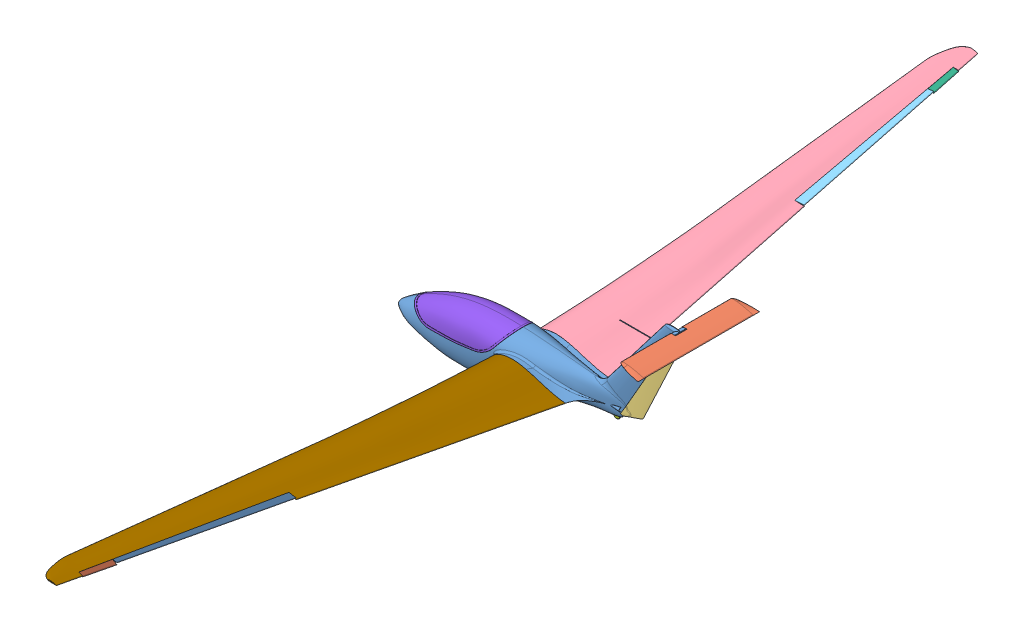
SolidWorks assembly G2, configuration Default. Lengths in mm.
Overall size (4857.56 2154.28 14974.87).
11 component instances, 11 part files, 23 mates.
Components (placement in the parent):
- fuselage-1: fuselage [Default] at (-2399.0476 -678.4623 -6.1761) size (4647.03 2154.28 817.52)
- Elevator-1: Elevator [Default] at (-2592.4679 -10.7116 -6.1761) x (0.990017 -0.140945 0) z (0 0 1) size (369.59 46.81 1973.39)
- TailFin-1: TailFin [Default] at (-2374.746 -692.1121 -425.4765) x (0.993311 0.003757 0.115405) z (-0.115405 0.064821 0.991201) size (1019.44 1537.55 79.37)
- RightWing-1: RightWing [Default] at (64.2546 7069.2767 -6.1761) x (0 0 -1) z (0.997564 -0.069756 0) size (7284.24 424.09 1503.14)
- RightFlap-1: RightFlap [Default] at (-780.4832 6967.3808 106.5214) x (0.005717 0.016013 -0.999855) z (0.999111 0.041673 0.00638) size (2595.89 151.47 516.44)
- RightAileron-1: RightAileron [Default] at (1721.4228 6989.7484 -243.8048) x (-0.016138 -0.029004 -0.999449) z (0.958774 -0.284078 -0.007237) size (509.26 36.38 165.41)
- TailWheel-1: TailWheel [Default] at (1188.0854 -633.4405 -16.4079) size (114.3 114.3 20.26)
- GlassShield-2: GlassShield [Default] at (-2399.0474 -678.4622 -6.1761) size (1997.95 819.79 898.09)
- LeftWing-1: LeftWing [Default] at (64.2546 7069.2767 -6.1761) x (0 0 -1) z (0.997564 -0.069756 0) size (7284.24 424.09 1503.14)
- LeftFlap-1: LeftFlap [Default] at (-1231.8601 6872.378 -176.6913) x (-0.008056 -0.024918 -0.999657) z (0.994746 0.101829 -0.010555) size (2595.89 151.47 516.44)
- LeftAileron-2: LeftAileron [Default] at (1280.1678 7047.2031 166.0311) x (0.011201 0.021593 -0.999704) z (0.973746 -0.22756 0.005995) size (509.26 36.38 165.41)
Mates (geometry in assembly coordinates):
- Concentric2: concentric aligned: cylinder of fuselage-1 through (1289.1653 -580.6894 -6.1761) axis (0.489718 0.871881 0) radius 6.35; cylinder of TailFin-1 through (1289.1653 -580.6894 -6.1761) axis (0.489718 0.871881 0) radius 6.35
- Coincident5: coincident anti-aligned: plane of fuselage-1 through (706.154 -539.7211 -361.7761) normal (0 0 -1); plane of RightWing-1 through (-435.1334 -423.7986 -361.7761) normal (0 0 1)
- Coincident6: coincident anti-aligned: plane of fuselage-1 through (27.8129 -445.2218 -209.3761) normal (-0.990524 0.137342 0); plane of RightWing-1 through (27.8129 -445.2218 -209.3761) normal (0.990524 -0.137342 0)
- Coincident7: coincident anti-aligned: plane of fuselage-1 through (-42.4323 -397.0174 -209.3761) normal (-0.137342 -0.990524 0); plane of RightWing-1 through (-42.4323 -397.0174 -209.3761) normal (0.137342 0.990524 0)
- Concentric3: concentric aligned: cylinder of RightWing-1 through (-27.4915 -301.4668 -4089.8299) axis (-0.138946 0.05853 -0.988569) radius 6.35; cylinder of RightFlap-1 through (-27.4915 -301.4668 -4089.8299) axis (-0.138946 0.05853 -0.988569) radius 6.35
- Coincident8: coincident anti-aligned: plane of RightWing-1 through (-73.6657 -909.8309 -4145.0529) normal (-0.138946 0.05853 -0.988569); plane of RightFlap-1 through (-5.3134 -910.2283 -4154.6836) normal (0.138946 -0.05853 0.988569)
- Concentric4: concentric aligned: cylinder of RightWing-1 through (-455.5258 -122.7684 -7134.4869) axis (0.138946 -0.05853 0.988569) radius 2.54; cylinder of RightAileron-1 through (-455.5258 -122.7684 -7134.4869) axis (0.138946 -0.05853 0.988569) radius 2.54
- Coincident9: coincident anti-aligned: plane of RightWing-1 through (-494.5323 -732.5444 -7139.4135) normal (0.138946 -0.05853 0.988569); plane of RightAileron-1 through (-625.4814 -709.5114 -7119.6445) normal (-0.138946 0.05853 -0.988569)
- Coincident10: coincident anti-aligned: plane of fuselage-1 through (1312.7204 -579.3537 -329.0605) normal (0.489718 0.871881 0); plane of TailFin-1 through (1349.8303 -600.1976 -323.5877) normal (-0.489718 -0.871881 0)
- Concentric5: concentric anti-aligned: cylinder of fuselage-1 through (2218.2489 1020.8694 -133.1761) axis (0 0 -1) radius 6.35; cylinder of Elevator-1 through (2218.2489 1020.8694 -196.2951) axis (0 0 1) radius 6.35
- Coincident11: coincident anti-aligned: plane of fuselage-1 through (2154.7125 1016.738 87.8039) normal (0 0 1); plane of Elevator-1 through (2154.7644 1025.7344 87.8039) normal (0 0 -1)
- Concentric6: concentric anti-aligned: cylinder of fuselage-1 through (1188.0854 -633.4405 499993.8239) axis (0 0 -1) radius 5.08; cylinder of TailWheel-1 through (1188.0854 -633.4405 3.851) axis (0 0 1) radius 2.54
- Coincident12: coincident anti-aligned: plane of fuselage-1 through (1246.6746 -603.6005 -15.1685) normal (0 0 1); plane of TailWheel-1 through (1190.6254 -633.4405 -15.1685) normal (0 0 -1)
- Concentric8: concentric anti-aligned: cylinder of fuselage-1 through (-2030.4334 -612.6736 -12.5261) axis (0 0 1) radius 3.175; cylinder of GlassShield-2 through (-2030.4334 -612.6736 6.5239) axis (0 0 -1) radius 3.175
- LimitAngle2: limit planar angle = 0.462434 rad aligned: plane of GlassShield-2 through (-2024.28 -603.4196 -3.0011) normal (0.525638 0.850708 0); plane of fuselage-1 through (-311924.6085 499347.8255 0.1739) normal (0.849955 0.526856 0)
- Coincident25: coincident anti-aligned: plane of fuselage-1 through (-2030.4334 -612.6736 -9.3511) normal (0 0 1); plane of GlassShield-2 through (-2030.4308 -612.6746 -9.3511) normal (0 0 -1)
- Coincident26: coincident anti-aligned: plane of fuselage-1 through (706.154 -539.7211 349.4239) normal (0 0 1); plane of LeftWing-1 through (-435.1334 -423.7986 349.4239) normal (0 0 -1)
- Coincident27: coincident anti-aligned: plane of fuselage-1 through (-42.4323 -397.0174 197.0239) normal (-0.137342 -0.990524 0); plane of LeftWing-1 through (-42.4323 -397.0174 197.0239) normal (0.137342 0.990524 0)
- Coincident28: coincident anti-aligned: plane of fuselage-1 through (-47.665 -434.7564 197.0239) normal (0.990524 -0.137342 0); plane of LeftWing-1 through (-47.665 -434.7564 197.0239) normal (-0.990524 0.137342 0)
- Concentric9: concentric aligned: cylinder of LeftWing-1 through (-27.4915 -301.4668 4077.4776) axis (-0.138946 0.05853 0.988569) radius 6.35; cylinder of LeftFlap-1 through (-27.4915 -301.4668 4077.4776) axis (-0.138946 0.05853 0.988569) radius 6.35
- Coincident30: coincident anti-aligned: plane of LeftWing-1 through (-73.6657 -909.8309 4132.7007) normal (-0.138946 0.05853 0.988569); plane of LeftFlap-1 through (31.6132 -907.2011 4147.3422) normal (0.138946 -0.05853 -0.988569)
- Coincident32: coincident anti-aligned: plane of LeftWing-1 through (-494.5323 -732.5444 7127.0613) normal (0.138946 -0.05853 -0.988569); plane of LeftAileron-2 through (-590.9732 -718.5344 7112.6767) normal (-0.138946 0.05853 0.988569)
- Concentric11: concentric aligned: cylinder of LeftWing-1 through (-455.5258 -122.7684 7122.1346) axis (0.138946 -0.05853 -0.988569) radius 2.54; cylinder of LeftAileron-2 through (-455.5258 -122.7684 7122.1346) axis (0.138946 -0.05853 -0.988569) radius 2.54
